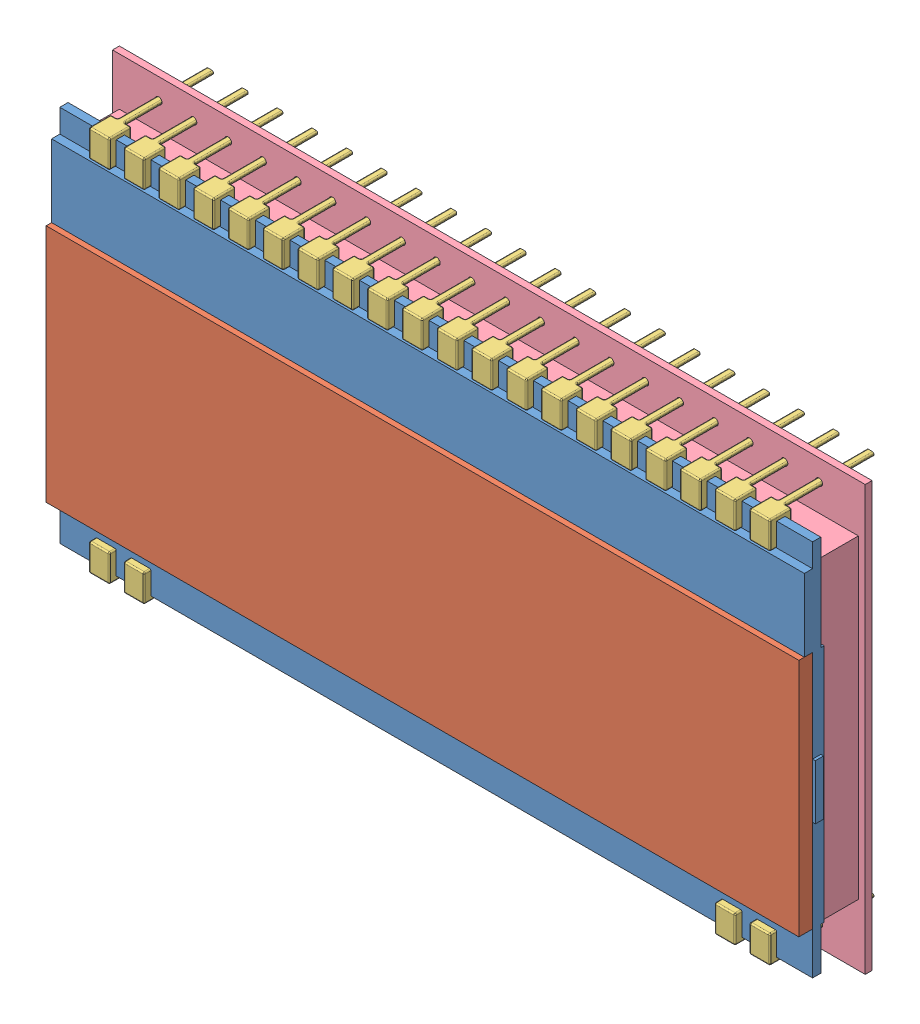
SolidWorks assembly EA-DOGM132, configuration Domyślna. Lengths in mm.
Overall size (55.2 31 8.6).
27 component instances, 4 part files, 19 mates.
Components (placement in the parent):
- LCD_base^EA-DOGM132-1: LCD_base^EA-DOGM132 [Domyślna] at origin size (55.2 27.6 1.45) (virtual)
- LCD_disp^EA-DOGM132-1: LCD_disp^EA-DOGM132 [Domyślna] at origin size (55 17.5 1) (virtual)
- LCD_pin^EA-DOGM132-1: LCD_pin^EA-DOGM132 [Domyślna] at origin size (1.5 2 8.1) (virtual)
- LCD_pin^EA-DOGM132-40: LCD_pin^EA-DOGM132 [Domyślna] at (2.54 0 0) size (1.5 2 8.1) (virtual)
- LCD_pin^EA-DOGM132-41: LCD_pin^EA-DOGM132 [Domyślna] at (45.72 0 0) size (1.5 2 8.1) (virtual)
- LCD_pin^EA-DOGM132-42: LCD_pin^EA-DOGM132 [Domyślna] at (48.26 0 0) size (1.5 2 8.1) (virtual)
- LCD_pin^EA-DOGM132-43: LCD_pin^EA-DOGM132 [Domyślna] at (-48.26 3.9 0) x (-1 0 0) z (0 0 1) size (1.5 2 8.1) (virtual)
- LCD_pin^EA-DOGM132-44: LCD_pin^EA-DOGM132 [Domyślna] at (-45.72 3.9 0) x (-1 0 0) z (0 0 1) size (1.5 2 8.1) (virtual)
- LCD_pin^EA-DOGM132-45: LCD_pin^EA-DOGM132 [Domyślna] at (-43.18 3.9 0) x (-1 0 0) z (0 0 1) size (1.5 2 8.1) (virtual)
- LCD_pin^EA-DOGM132-46: LCD_pin^EA-DOGM132 [Domyślna] at (-40.64 3.9 0) x (-1 0 0) z (0 0 1) size (1.5 2 8.1) (virtual)
- LCD_pin^EA-DOGM132-47: LCD_pin^EA-DOGM132 [Domyślna] at (-38.1 3.9 0) x (-1 0 0) z (0 0 1) size (1.5 2 8.1) (virtual)
- LCD_pin^EA-DOGM132-48: LCD_pin^EA-DOGM132 [Domyślna] at (-35.56 3.9 0) x (-1 0 0) z (0 0 1) size (1.5 2 8.1) (virtual)
- LCD_pin^EA-DOGM132-49: LCD_pin^EA-DOGM132 [Domyślna] at (-33.02 3.9 0) x (-1 0 0) z (0 0 1) size (1.5 2 8.1) (virtual)
- LCD_pin^EA-DOGM132-50: LCD_pin^EA-DOGM132 [Domyślna] at (-30.48 3.9 0) x (-1 0 0) z (0 0 1) size (1.5 2 8.1) (virtual)
- LCD_pin^EA-DOGM132-51: LCD_pin^EA-DOGM132 [Domyślna] at (-27.94 3.9 0) x (-1 0 0) z (0 0 1) size (1.5 2 8.1) (virtual)
- LCD_pin^EA-DOGM132-52: LCD_pin^EA-DOGM132 [Domyślna] at (-25.4 3.9 0) x (-1 0 0) z (0 0 1) size (1.5 2 8.1) (virtual)
- LCD_pin^EA-DOGM132-53: LCD_pin^EA-DOGM132 [Domyślna] at (-22.86 3.9 0) x (-1 0 0) z (0 0 1) size (1.5 2 8.1) (virtual)
- LCD_pin^EA-DOGM132-54: LCD_pin^EA-DOGM132 [Domyślna] at (-20.32 3.9 0) x (-1 0 0) z (0 0 1) size (1.5 2 8.1) (virtual)
- LCD_pin^EA-DOGM132-55: LCD_pin^EA-DOGM132 [Domyślna] at (-17.78 3.9 0) x (-1 0 0) z (0 0 1) size (1.5 2 8.1) (virtual)
- LCD_pin^EA-DOGM132-56: LCD_pin^EA-DOGM132 [Domyślna] at (-15.24 3.9 0) x (-1 0 0) z (0 0 1) size (1.5 2 8.1) (virtual)
- LCD_pin^EA-DOGM132-57: LCD_pin^EA-DOGM132 [Domyślna] at (-12.7 3.9 0) x (-1 0 0) z (0 0 1) size (1.5 2 8.1) (virtual)
- LCD_pin^EA-DOGM132-58: LCD_pin^EA-DOGM132 [Domyślna] at (-10.16 3.9 0) x (-1 0 0) z (0 0 1) size (1.5 2 8.1) (virtual)
- LCD_pin^EA-DOGM132-59: LCD_pin^EA-DOGM132 [Domyślna] at (-7.62 3.9 0) x (-1 0 0) z (0 0 1) size (1.5 2 8.1) (virtual)
- LCD_pin^EA-DOGM132-60: LCD_pin^EA-DOGM132 [Domyślna] at (-5.08 3.9 0) x (-1 0 0) z (0 0 1) size (1.5 2 8.1) (virtual)
- LCD_pin^EA-DOGM132-61: LCD_pin^EA-DOGM132 [Domyślna] at (-2.54 3.9 0) x (-1 0 0) z (0 0 1) size (1.5 2 8.1) (virtual)
- LCD_pin^EA-DOGM132-62: LCD_pin^EA-DOGM132 [Domyślna] at (0 3.9 0) x (-1 0 0) z (0 0 1) size (1.5 2 8.1) (virtual)
- LCD_backlight^EA-DOGM132-1: LCD_backlight^EA-DOGM132 [Domyślna] at (0 0 -0.85) x (-1 0 0) z (0 0 -1) size (55 31 3.5) (virtual)
Mates (geometry in assembly coordinates):
- InPlace1: in place: plane of ? through (0 0 0) normal (0 0 1); moOrthogonalPlaneRef_w of ? through (0 0 0) normal (0 1 0); plane of ? through (0 0 0) normal (1 0 0); unknown of ?
- Coincident1: coincident aligned: 
- Coincident2: coincident aligned: plane of Part4^Assem2-1 through (0 0 0) normal (0 1 0)
- Coincident3: coincident anti-aligned: plane of Part4^Assem2-1 through (0 0 0) normal (1 0 0)
- InPlace2: in place: plane of ? through (0 0 0) normal (0 0 1); plane of ? through (0 0 0) normal (0 1 0); plane of ? through (0 0 0) normal (1 0 0); unknown of ?
- Coincident4: coincident aligned: 
- Coincident5: coincident aligned: plane of Part5^Assem2-1 through (0 0 0) normal (0 1 0)
- Coincident6: coincident anti-aligned: plane of Part5^Assem2-1 through (0 0 0) normal (1 0 0)
- InPlace3: in place: plane of ? through (0 0 0) normal (0 0 1); plane of ? through (0 0 0) normal (0 0 1); plane of ? through (0 0 0) normal (0 0 1); plane of ? through (0 0 0) normal (0 1 0); plane of ? through (0 0 0) normal (0 0 1); plane of ? through (0 0 0) normal (1 0 0); plane of ? through (0 0 0) normal (0 0 1); unknown of ?
- Coincident7: coincident aligned: plane of ?; plane of ?
- Coincident8: coincident aligned: moOrthogonalPlaneRef_w of Part4^Assem2-1 through (0 0 0) normal (0 1 0); plane of Part6^Assem2-1 through (0 0 0) normal (0 1 0)
- Coincident9: coincident anti-aligned: moOrthogonalPlaneRef_w of Part4^Assem2-1 through (0 0 0) normal (-1 0 0); plane of Part6^Assem2-1 through (0 0 0) normal (1 0 0)
- Coincident13: coincident anti-aligned: plane of Part4^Assem2-1 through (-27.5 15.75 -0.6) normal (0 1 0); plane of Part6^Assem2-43 through (-23.38 15.75 -1.1) normal (0 -1 0)
- Coincident14: coincident anti-aligned: plane of Part4^Assem2-1 through (0 0 0) normal (0 0 1); plane of Part6^Assem2-43 through (-48.26 3.9 0) normal (0 0 -1)
- Coincident16: coincident aligned: line of Part6^Assem2-43 through (1.6 -24.88 15.75) axis (0 0 -1)
- InPlace4: in place: plane of ? through (0 0 -0.85) normal (0 0 -1); plane of LCD_backlight^EA-DOGM132-1 through (0 0 -0.85) normal (0 0 -1); plane of ? through (0 0 -0.85) normal (0 0 -1); plane of LCD_backlight^EA-DOGM132-1 through (0 0 -0.85) normal (0 1 0); plane of ? through (0 0 -0.85) normal (0 0 -1); plane of LCD_backlight^EA-DOGM132-1 through (0 0 -0.85) normal (-1 0 0); plane of ? through (0 0 -0.85) normal (0 0 -1); unknown of LCD_backlight^EA-DOGM132-1
- Coincident17: coincident aligned: plane of ?; plane of ?
- Coincident18: coincident aligned: moOrthogonalPlaneRef_w of LCD_base^Assem2-1 through (0 0 -0.85) normal (0 1 0); plane of LCD_backlight^Assem2-1 through (0 0 -0.85) normal (0 1 0)
- Coincident19: coincident anti-aligned: moOrthogonalPlaneRef_w of LCD_base^Assem2-1 through (0 0 -0.85) normal (1 0 0); plane of LCD_backlight^Assem2-1 through (0 0 -0.85) normal (-1 0 0)
